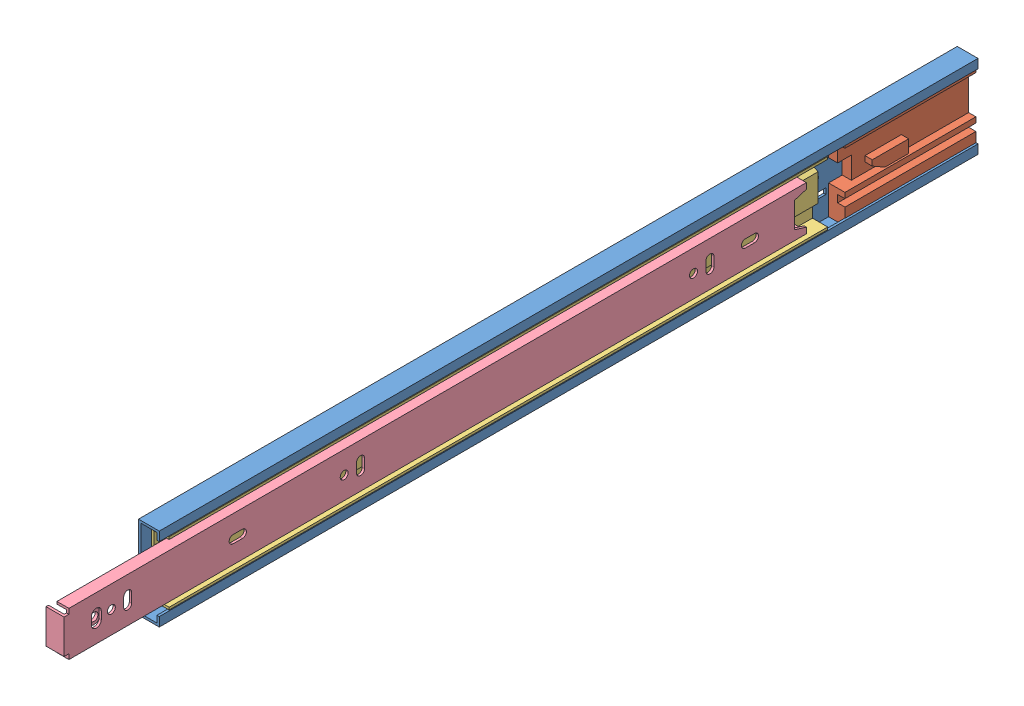
SolidWorks assembly 2831110, configuration Default. Lengths in mm.
Overall size (3.17 11.42 125.91).
4 component instances, 4 part files, 9 mates.
Components (placement in the parent):
- 3832-0045TR Outer Member-1: 3832-0045TR Outer Member [Default] at origin size (2.85 11.42 112.5)
- 3832TR Touch Release-1: 3832TR Touch Release [Default] at (-5.6264 0.6754 178.2964) x (0 -1 0) z (1 0 0) size (10.79 18 2.25)
- 3832-0045TR Inter-1: 3832-0045TR Inter [Default] at (-0.6578 0.0001 415.8579) x (0 1 0) z (0 0 -1) size (8.7 2.43 90.5)
- 3832-0045TR Inner Member-1: 3832-0045TR Inner Member [Default] at (-1.9688 0 36.7668) x (0 -1 0) z (0 0 1) size (6.1 2.47 102)
Mates (geometry in assembly coordinates):
- Width1: width anti-aligned: plane of 3832-0045TR Outer Member-1 through (-3.1394 5.7125 168.9579) normal (0 1 0); plane of 3832-0045TR Outer Member-1 through (-3.1394 -5.7125 281.4579) normal (0 -1 0); plane of 3832-0045TR Inter-1 through (-2.7144 4.35 280.1079) normal (0 1 0); plane of 3832-0045TR Inter-1 through (-0.2894 -4.35 280.1079) normal (0 -1 0)
- Width2: width anti-aligned: plane of 3832-0045TR Outer Member-1 through (-3.1394 -5.7125 281.4579) normal (0 -1 0); plane of 3832-0045TR Outer Member-1 through (-3.1394 5.7125 168.9579) normal (0 1 0); plane of 3832-0045TR Inner Member-1 through (0.0356 3.05 294.8711) normal (0 1 0); plane of 3832-0045TR Inner Member-1 through (0.0356 -3.05 192.8711) normal (0 -1 0)
- Coincident1: coincident aligned: plane of 3832-0045TR Outer Member-1 through (-0.2894 0 168.9579) normal (1 0 0); plane of 3832-0045TR Inter-1 through (-0.2894 4.35 280.1079) normal (1 0 0)
- Distance1: distance = 3.175 mm anti-aligned: plane of 3832-0045TR Inner Member-1 through (0.0356 0 192.8711) normal (1 0 0); plane of 3832-0045TR Outer Member-1 through (-3.1394 0 168.9579) normal (-1 0 0)
- Linear/Linear Coupler4: linear coupler = 48.75 : 111.5 mm: line of 3832-0045TR Inter-1 through (-0.2894 4.025 280.1079) axis (0 0 -1); line of 3832-0045TR Inner Member-1 through (0.0356 3.05 294.1961) axis (0 0 -1)
- LimitDistance3: limit distance = -1.35 mm aligned: plane of 3832-0045TR Outer Member-1 through (-3.1394 5.7125 281.4579) normal (0 0 1); plane of 3832-0045TR Inter-1 through (-1.6156 0 280.1079) normal (0 0 1)
- Coincident2: coincident aligned: plane of 3832-0045TR Outer Member-1 through (-3.1394 -5.7125 168.9579) normal (0 0 -1); plane of 3832TR Touch Release-1 through (-0.5719 5.395 168.9579) normal (0 0 -1)
- Coincident3: coincident anti-aligned: plane of 3832-0045TR Outer Member-1 through (-2.8219 5.395 168.9579) normal (1 0 0); plane of 3832TR Touch Release-1 through (-2.8219 0 177.9579) normal (-1 0 0)
- Coincident4: coincident anti-aligned: plane of 3832-0045TR Outer Member-1 through (-2.8219 -5.395 168.9579) normal (0 1 0); plane of 3832TR Touch Release-1 through (-0.5719 -5.395 168.9579) normal (0 -1 0)
